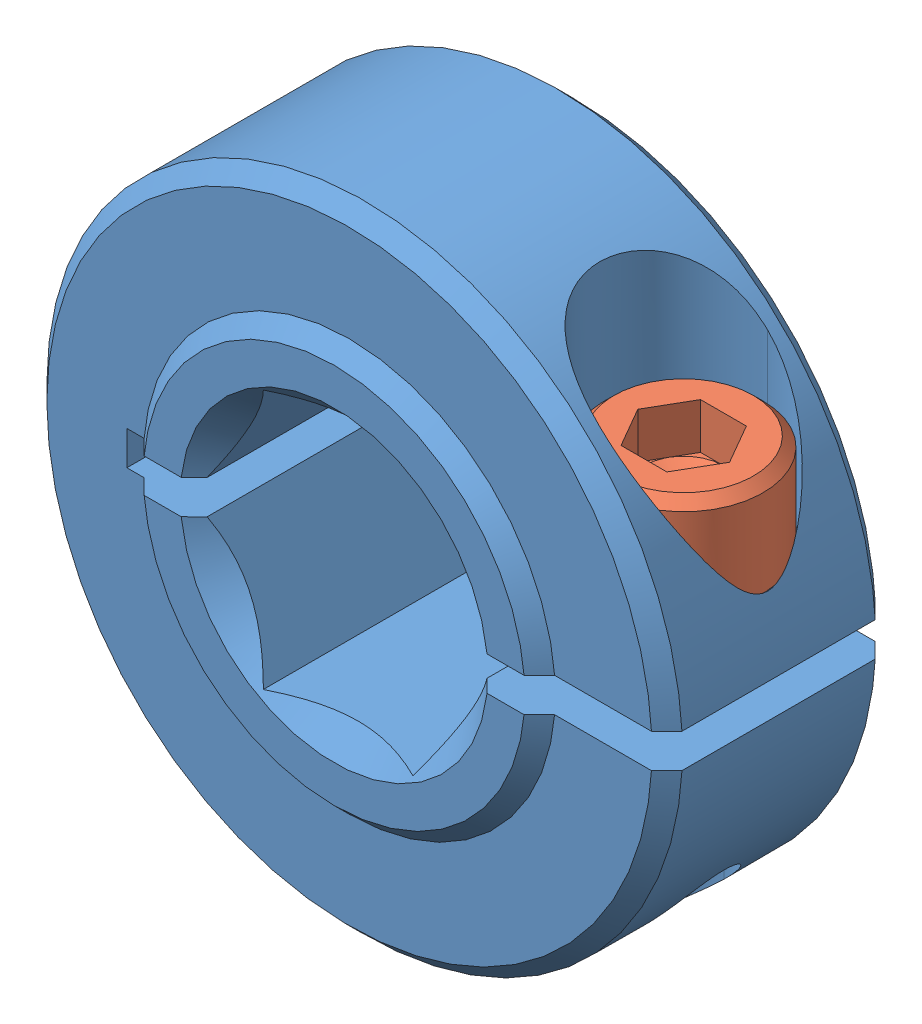
SolidWorks assembly am-1526 500Hex HD Collar Clamp, configuration Default. Lengths in mm.
Overall size (31.73 31.75 12.7).
3 component instances, 2 part files, 0 mates.
Components (placement in the parent):
- am-1526 500Hex HD Collar Clamp.STEP-1: am-1526 500Hex HD Collar Clamp.STEP [Default] at origin size (31.73 31.75 12.7)
  - am-1238a 500Hex Collar Clamp Body.STEP-1: am-1238a 500Hex Collar Clamp Body.STEP [Default] at (-94.2794 15.3021 33.01) size (31.73 31.75 12.7)
  - 10-32x0500_shcs_HX-SHCS 0.19-32x1.375x1-C.STEP-1: 10-32x0500_shcs_HX-SHCS 0.19-32x1.375x1-C.STEP [Default] at (-83.1669 24.154 39.36) x (0 -1 0) z (0 0 1) size (17.53 7.94 7.94)
